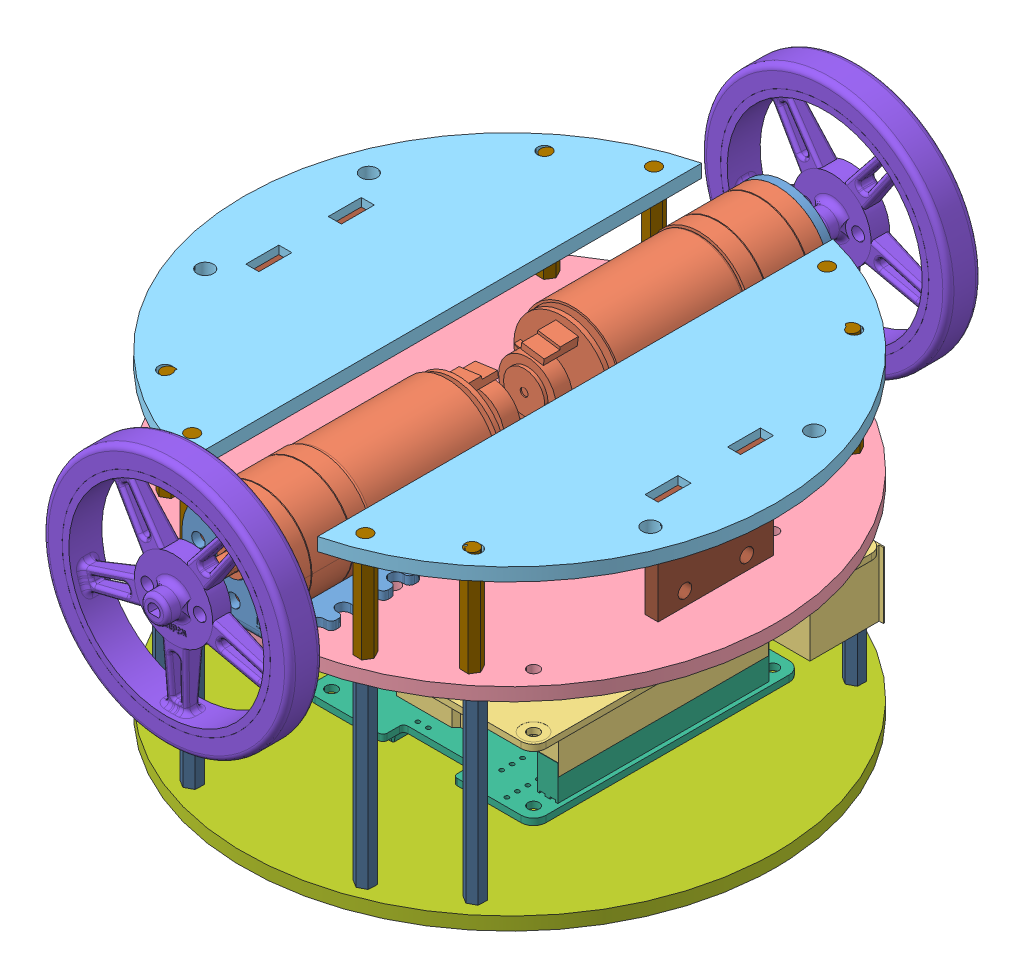
SolidWorks assembly Fleet v1.0, configuration Default. Lengths in mm.
Overall size (129 95.35 170.77).
30 component instances, 11 part files, 66 mates.
Components (placement in the parent):
- pololu-25d-mm-metal-gearmotor-bracket-1: pololu-25d-mm-metal-gearmotor-bracket [Default] at (11.9651 32.2947 52.3664) size (25 27 52)
- 25d-metal-gearmotor-20.4-encoder.step-1: 25d-metal-gearmotor-20.4-encoder.step [Default] at (41.8401 33.2947 46.4914) x (-1 0 0) z (0 0 1) size (25 32.85 74)
- 25d-metal-gearmotor-20.4-encoder.step-2: 25d-metal-gearmotor-20.4-encoder.step [Default] at (-19.9099 33.2947 -46.7586) x (1 0 0) z (0 0 -1) size (25 32.85 74)
- pololu-25d-mm-metal-gearmotor-bracket-2: pololu-25d-mm-metal-gearmotor-bracket [Default] at (9.9651 32.2947 -52.6336) x (-1 0 0) z (0 0 -1) size (25 27 52)
- Rpi3Bplus-1: Rpi3Bplus [Default] at (3.2536 5.5943 42.3664) x (0 0 -1) z (-1 0 0) size (87.03 17.52 58.47)
- Main Plate 1-1: Main Plate 1 [Default] at (25.4205 18.7947 0.2329) x (1 0 0) z (0 -1 0) size (129 129 3.17)
- SubPlate 1-1: SubPlate 1 [Default] at (26.8901 43.9697 0.2329) x (1 0 0) z (0 -1 0) size (48.58 125.01 3.17)
- SubPlate 1-2: SubPlate 1 [Default] at (-4.9599 43.9697 -0.5) x (-1 0 0) z (0 -1 0) size (48.58 125.01 3.17)
- dual-tb9051ftg-motor-driver-raspberry-pi.step-1: dual-tb9051ftg-motor-driver-raspberry-pi.step [Default] at (3.2536 -9.9043 42.3664) x (0 0 -1) z (0 -1 0) size (65 56 20.07)
- Top Plate-1: Top Plate [Default] at (25.9074 -29.3803 -5.7671) x (1 0 0) z (0 -1 0) size (129 129 3.17)
- pololu-wheel-60x8mm-black-1: pololu-wheel-60x8mm-black [Default] at (11.4421 32.7947 79.6164) x (0 0 -1) z (-1 0 0) size (11 60 60)
- pololu-wheel-60x8mm-black-2: pololu-wheel-60x8mm-black [Default] at (11.3417 32.7947 -80.154) x (0 0 -1) z (-1 0 0) size (11 60 60)
- 22mm Standoff-1: 22mm Standoff [Default] at (31.9651 18.7947 55.8664) size (4.39 28.35 3.87)
- 22mm Standoff-2: 22mm Standoff [Default] at (-25.8852 18.7947 -46.1336) size (4.39 28.35 3.87)
- 22mm Standoff-3: 22mm Standoff [Default] at (-10.0349 18.7947 -56.1336) size (4.39 28.35 3.87)
- 22mm Standoff-4: 22mm Standoff [Default] at (47.8154 18.7947 -46.1336) size (4.39 28.35 3.87)
- 22mm Standoff-5: 22mm Standoff [Default] at (47.8154 18.7947 45.8664) size (4.39 28.35 3.87)
- 22mm Standoff-6: 22mm Standoff [Default] at (31.9651 18.7947 -56.1336) size (4.39 28.35 3.87)
- 22mm Standoff-7: 22mm Standoff [Default] at (-10.0349 18.7947 55.8664) size (4.39 28.35 3.87)
- 22mm Standoff-8: 22mm Standoff [Default] at (-25.8852 40.7947 45.8664) x (0.837169 0 0.546944) z (0.546944 0 -0.837169) size (4.39 28.35 3.87)
- 45mm Standoff-1: 45mm Standoff [Default] at (-10.0349 15.6197 55.8664) x (-0.837169 0 -0.546944) z (-0.546944 0 0.837169) size (4.39 48.18 3.83)
- 45mm Standoff-2: 45mm Standoff [Default] at (31.9651 15.6197 55.8664) x (0.837169 0 0.546944) z (0.546944 0 -0.837169) size (4.39 48.18 3.83)
- 45mm Standoff-3: 45mm Standoff [Default] at (-10.0349 15.6197 -56.1336) x (-0.837169 0 -0.546944) z (-0.546944 0 0.837169) size (4.39 48.18 3.83)
- 45mm Standoff-4: 45mm Standoff [Default] at (-26.6691 15.6197 -46.1336) x (-0.837169 0 -0.546944) z (-0.546944 0 0.837169) size (4.39 48.18 3.83)
- 45mm Standoff-6: 45mm Standoff [Default] at (48.5993 15.6197 -46.1336) x (-0.837169 0 -0.546944) z (-0.546944 0 0.837169) size (4.39 48.18 3.83)
- 45mm Standoff-7: 45mm Standoff [Default] at (31.9651 15.6197 -56.1336) x (-0.837169 0 -0.546944) z (-0.546944 0 0.837169) size (4.39 48.18 3.83)
- 45mm Standoff-8: 45mm Standoff [Default] at (48.5993 15.6197 45.8664) x (-0.837169 0 -0.546944) z (-0.546944 0 0.837169) size (4.39 48.18 3.83)
- 45mm Standoff-9: 45mm Standoff [Default] at (-26.6691 15.6197 45.8664) x (0.837169 0 0.546944) z (0.546944 0 -0.837169) size (4.39 48.18 3.83)
- Time of Flight Holder-1: Time of Flight Holder [Default] at (-35.8599 28.7947 -0.1336) x (0 0 -1) z (-1 0 0) size (28 26.35 3.17)
- Time of Flight Holder-2: Time of Flight Holder [Default] at (60.9651 28.7947 -0.1336) x (0 0 -1) z (-1 0 0) size (28 26.35 3.17)
Mates (geometry in assembly coordinates):
- Concentric1: concentric: circle of pololu-25d-mm-metal-gearmotor-bracket-1; circle of 25d-metal-gearmotor-20.4-encoder.step-1
- Concentric2: concentric: circle of pololu-25d-mm-metal-gearmotor-bracket-1; circle of 25d-metal-gearmotor-20.4-encoder.step-1
- Coincident1: coincident: plane of pololu-25d-mm-metal-gearmotor-bracket-1 through (23.4651 20.7947 64.8664) normal (0 0 -1); plane of 25d-metal-gearmotor-20.4-encoder.step-1 through (10.9651 33.2947 64.8664) normal (0 0 1)
- Concentric3: concentric: circle of 25d-metal-gearmotor-20.4-encoder.step-2; circle of pololu-25d-mm-metal-gearmotor-bracket-2
- Concentric4: concentric: circle of 25d-metal-gearmotor-20.4-encoder.step-2; circle of pololu-25d-mm-metal-gearmotor-bracket-2
- Coincident2: coincident: plane of 25d-metal-gearmotor-20.4-encoder.step-2 through (10.9651 33.2947 -65.1336) normal (0 0 -1); plane of pololu-25d-mm-metal-gearmotor-bracket-2 through (-1.5349 20.7947 -65.1336) normal (0 0 1)
- Coincident3: coincident: plane of pololu-25d-mm-metal-gearmotor-bracket-1 through (23.4651 18.7947 64.8664) normal (0 -1 0); plane of pololu-25d-mm-metal-gearmotor-bracket-2 through (-1.5349 18.7947 -65.1336) normal (0 -1 0)
- Coincident5: coincident: plane of pololu-25d-mm-metal-gearmotor-bracket-1 through (-1.5349 21.4297 64.2314) normal (-1 0 0); plane of pololu-25d-mm-metal-gearmotor-bracket-2 through (-1.5349 21.4297 -67.1336) normal (-1 0 0)
- Distance6: distance = 10 mm: plane of Rpi3Bplus-1 through (6.2536 5.6197 -39.6336) normal (0 1 0); plane of Main Plate 1-1 through (10.9651 15.6197 -0.1336) normal (0 -1 0)
- Concentric13: concentric: circle of Main Plate 1-1; circle of SubPlate 1-1
- Concentric14: concentric: circle of Main Plate 1-1; circle of SubPlate 1-1
- Distance7: distance = 22 mm: plane of SubPlate 1-1 through (10.9651 40.7947 -0.1336) normal (0 -1 0); plane of Main Plate 1-1 through (10.9651 18.7947 -0.1336) normal (0 1 0)
- Concentric15: concentric: circle of Main Plate 1-1; circle of SubPlate 1-2
- Concentric16: concentric: circle of Main Plate 1-1; circle of SubPlate 1-2
- Distance8: distance = 22 mm: plane of SubPlate 1-2 through (10.9651 40.7947 -0.1336) normal (0 -1 0); plane of Main Plate 1-1 through (10.9651 18.7947 -0.1336) normal (0 1 0)
- Distance9: distance = 14 mm: plane of Rpi3Bplus-1 through (56.2536 4.0957 39.3664) normal (0 -1 0); plane of dual-tb9051ftg-motor-driver-raspberry-pi.step-1 through (6.2536 -9.9043 39.3664) normal (0 1 0)
- Coincident28: coincident: plane of Rpi3Bplus-1 through (59.2536 4.1211 39.3664) normal (1 0 0); plane of dual-tb9051ftg-motor-driver-raspberry-pi.step-1 through (59.2536 -11.4791 39.3664) normal (1 0 0)
- Coincident29: coincident: plane of Rpi3Bplus-1 through (6.2536 4.1211 42.3664) normal (0 0 1); plane of dual-tb9051ftg-motor-driver-raspberry-pi.step-1 through (40.7536 -11.4791 42.3664) normal (0 0 1)
- Concentric17: concentric: circle of Main Plate 1-1; circle of Top Plate-1
- Concentric18: concentric: cylinder of Main Plate 1-1 through (31.9651 15.6197 55.8664) axis (0 1 0) radius 1.65; circle of Top Plate-1
- Distance10: distance = 45 mm: plane of Top Plate-1 through (10.9651 -29.3803 -0.1336) normal (0 1 0); plane of Main Plate 1-1 through (10.9651 15.6197 -0.1336) normal (0 -1 0)
- Coincident34: coincident: plane of 25d-metal-gearmotor-20.4-encoder.step-1 through (10.9651 31.7947 69.3664) normal (0 -1 0); plane of pololu-wheel-60x8mm-black-1 through (12.5601 31.7947 75.6164) normal (0 1 0)
- Parallel8: parallel: cylinder of 25d-metal-gearmotor-20.4-encoder.step-1 through (10.9651 33.2947 64.8664) axis (0 0 1) radius 2; cylinder of pololu-wheel-60x8mm-black-1 through (11.4421 32.7947 75.6164) axis (0 0 1) radius 1.5
- Coincident38: coincident: plane of 25d-metal-gearmotor-20.4-encoder.step-2 through (10.9651 31.7947 -69.6336) normal (0 -1 0); plane of pololu-wheel-60x8mm-black-2 through (12.4598 31.7947 -84.154) normal (0 1 0)
- Parallel9: parallel: cylinder of 25d-metal-gearmotor-20.4-encoder.step-2 through (10.9651 33.2947 -65.1336) axis (0 0 -1) radius 2; cylinder of pololu-wheel-60x8mm-black-2 through (11.3417 32.7947 -84.154) axis (0 0 1) radius 1.5
- Concentric27: concentric: cylinder of Main Plate 1-1 through (31.9651 15.6197 55.8664) axis (0 1 0) radius 1.65; cylinder of 22mm Standoff-1 through (31.9651 15.6197 55.8664) axis (0 1 0) radius 1.65
- Concentric28: concentric: circle of SubPlate 1-1; cylinder of 22mm Standoff-1 through (31.9651 43.9697 55.8664) axis (0 -1 0) radius 1.65
- Coincident40: coincident: plane of SubPlate 1-1 through (10.9651 40.7947 -0.1336) normal (0 -1 0); plane of 22mm Standoff-1 through (31.9651 40.7947 55.8664) normal (0 1 0)
- Concentric29: concentric: cylinder of Main Plate 1-1 through (47.8154 15.6197 45.8664) axis (0 1 0) radius 1.65; cylinder of 22mm Standoff-5 through (47.8154 15.6197 45.8664) axis (0 1 0) radius 1.65
- Coincident41: coincident: plane of Main Plate 1-1 through (10.9651 18.7947 -0.1336) normal (0 1 0); plane of 22mm Standoff-5 through (47.8154 18.7947 45.8664) normal (0 -1 0)
- Concentric30: concentric: cylinder of Main Plate 1-1 through (47.8154 15.6197 -46.1336) axis (0 1 0) radius 1.65; cylinder of 22mm Standoff-4 through (47.8154 15.6197 -46.1336) axis (0 1 0) radius 1.65
- Coincident42: coincident: plane of Main Plate 1-1 through (10.9651 18.7947 -0.1336) normal (0 1 0); plane of 22mm Standoff-4 through (47.8154 18.7947 -46.1336) normal (0 -1 0)
- Concentric31: concentric: cylinder of Main Plate 1-1 through (31.9651 15.6197 -56.1336) axis (0 1 0) radius 1.65; cylinder of 22mm Standoff-6 through (31.9651 15.6197 -56.1336) axis (0 1 0) radius 1.65
- Coincident43: coincident: plane of Main Plate 1-1 through (10.9651 18.7947 -0.1336) normal (0 1 0); plane of 22mm Standoff-6 through (31.9651 18.7947 -56.1336) normal (0 -1 0)
- Concentric32: concentric: cylinder of Main Plate 1-1 through (-10.0349 15.6197 -56.1336) axis (0 1 0) radius 1.65; cylinder of 22mm Standoff-3 through (-10.0349 15.6197 -56.1336) axis (0 1 0) radius 1.65
- Coincident44: coincident: plane of Main Plate 1-1 through (10.9651 18.7947 -0.1336) normal (0 1 0); plane of 22mm Standoff-3 through (-10.0349 18.7947 -56.1336) normal (0 -1 0)
- Concentric33: concentric: cylinder of Main Plate 1-1 through (-25.8852 15.6197 -46.1336) axis (0 1 0) radius 1.65; cylinder of 22mm Standoff-2 through (-25.8852 15.6197 -46.1336) axis (0 1 0) radius 1.65
- Coincident45: coincident: plane of Main Plate 1-1 through (10.9651 18.7947 -0.1336) normal (0 1 0); plane of 22mm Standoff-2 through (-25.8852 18.7947 -46.1336) normal (0 -1 0)
- Concentric34: concentric: cylinder of Main Plate 1-1 through (-25.8852 15.6197 45.8664) axis (0 1 0) radius 1.65; cylinder of 22mm Standoff-8 through (-25.8852 43.9697 45.8664) axis (0 -1 0) radius 1.65
- Coincident46: coincident: plane of Main Plate 1-1 through (10.9651 18.7947 -0.1336) normal (0 1 0); plane of 22mm Standoff-8 through (-25.8852 18.7947 45.8664) normal (0 -1 0)
- Concentric35: concentric: cylinder of Main Plate 1-1 through (-10.0349 15.6197 55.8664) axis (0 1 0) radius 1.65; cylinder of 22mm Standoff-7 through (-10.0349 15.6197 55.8664) axis (0 1 0) radius 1.65
- Coincident47: coincident: plane of Main Plate 1-1 through (10.9651 18.7947 -0.1336) normal (0 1 0); plane of 22mm Standoff-7 through (-10.0349 18.7947 55.8664) normal (0 -1 0)
- Concentric36: concentric: cylinder of Top Plate-1 through (-26.6691 -32.5553 45.8664) axis (0 1 0) radius 1.65; cylinder of 45mm Standoff-9 through (-26.6691 -32.5553 45.8664) axis (0 1 0) radius 1.65
- Coincident48: coincident: plane of Main Plate 1-1 through (10.9651 15.6197 -0.1336) normal (0 -1 0); plane of 45mm Standoff-9 through (-26.6691 15.6197 45.8664) normal (0 1 0)
- Coincident49: coincident: plane of Main Plate 1-1 through (10.9651 15.6197 -0.1336) normal (0 -1 0); plane of 45mm Standoff-1 through (-10.0349 15.6197 55.8664) normal (0 1 0)
- Concentric37: concentric: cylinder of Top Plate-1 through (-10.0349 -32.5553 55.8664) axis (0 1 0) radius 1.65; cylinder of 45mm Standoff-1 through (-10.0349 -32.5553 55.8664) axis (0 1 0) radius 1.65
- Coincident50: coincident: plane of Main Plate 1-1 through (10.9651 15.6197 -0.1336) normal (0 -1 0); plane of 45mm Standoff-2 through (31.9651 15.6197 55.8664) normal (0 1 0)
- Concentric38: concentric: cylinder of Top Plate-1 through (31.9651 -32.5553 55.8664) axis (0 1 0) radius 1.65; cylinder of 45mm Standoff-2 through (31.9651 -32.5553 55.8664) axis (0 1 0) radius 1.65
- Coincident51: coincident: plane of Main Plate 1-1 through (10.9651 15.6197 -0.1336) normal (0 -1 0); plane of 45mm Standoff-8 through (48.5993 15.6197 45.8664) normal (0 1 0)
- Concentric39: concentric: cylinder of Top Plate-1 through (48.5993 -32.5553 45.8664) axis (0 1 0) radius 1.65; cylinder of 45mm Standoff-8 through (48.5993 -32.5553 45.8664) axis (0 1 0) radius 1.65
- Coincident52: coincident: plane of Main Plate 1-1 through (10.9651 15.6197 -0.1336) normal (0 -1 0); plane of 45mm Standoff-6 through (48.5993 15.6197 -46.1336) normal (0 1 0)
- Concentric40: concentric: cylinder of Top Plate-1 through (48.5993 -32.5553 -46.1336) axis (0 1 0) radius 1.65; cylinder of 45mm Standoff-6 through (48.5993 -32.5553 -46.1336) axis (0 1 0) radius 1.65
- Coincident53: coincident: plane of Main Plate 1-1 through (10.9651 15.6197 -0.1336) normal (0 -1 0); plane of 45mm Standoff-7 through (31.9651 15.6197 -56.1336) normal (0 1 0)
- Concentric41: concentric: cylinder of Top Plate-1 through (31.9651 -32.5553 -56.1336) axis (0 1 0) radius 1.65; cylinder of 45mm Standoff-7 through (31.9651 -32.5553 -56.1336) axis (0 1 0) radius 1.65
- Coincident54: coincident: plane of Main Plate 1-1 through (10.9651 15.6197 -0.1336) normal (0 -1 0); plane of 45mm Standoff-3 through (-10.0349 15.6197 -56.1336) normal (0 1 0)
- Concentric42: concentric: cylinder of Top Plate-1 through (-10.0349 -32.5553 -56.1336) axis (0 1 0) radius 1.65; cylinder of 45mm Standoff-3 through (-10.0349 -32.5553 -56.1336) axis (0 1 0) radius 1.65
- Coincident55: coincident: plane of Main Plate 1-1 through (10.9651 15.6197 -0.1336) normal (0 -1 0); plane of 45mm Standoff-4 through (-26.6691 15.6197 -46.1336) normal (0 1 0)
- Concentric43: concentric: cylinder of Top Plate-1 through (-26.6691 -32.5553 -46.1336) axis (0 1 0) radius 1.65; cylinder of 45mm Standoff-4 through (-26.6691 -32.5553 -46.1336) axis (0 1 0) radius 1.65
- Concentric44: concentric: cylinder of Rpi3Bplus-1 through (55.7536 4.1211 38.8664) axis (0 1 0) radius 1.375; cylinder of Main Plate 1-1 through (55.7536 15.6197 38.8664) axis (0 1 0) radius 1.4
- Concentric45: concentric: cylinder of Rpi3Bplus-1 through (6.7536 4.1211 -19.1336) axis (0 1 0) radius 1.375; cylinder of Main Plate 1-1 through (6.7536 15.6197 -19.1336) axis (0 1 0) radius 1.4
- Coincident56: coincident: plane of Main Plate 1-1 through (10.9651 18.7947 -0.1336) normal (0 1 0); plane of Time of Flight Holder-1 through (-39.0349 18.7947 -0.1336) normal (0 -1 0)
- Coincident58: coincident: line of Main Plate 1-1 through (-39.0349 15.6197 -6.1336) axis (0 0 -1); line of Time of Flight Holder-1 through (-39.0349 15.6197 -6.1336) axis (0 0 -1)
- Coincident59: coincident: line of Main Plate 1-1 through (-39.0349 15.6197 -14.1336) axis (1 0 0); line of Time of Flight Holder-1 through (-39.0349 15.6197 -14.1336) axis (1 0 0)
- Coincident60: coincident: plane of Main Plate 1-1 through (10.9651 18.7947 -0.1336) normal (0 1 0); plane of Time of Flight Holder-2 through (57.7901 18.7947 -0.1336) normal (0 -1 0)
- Coincident61: coincident: line of Main Plate 1-1 through (57.7901 15.6197 -14.1336) axis (1 0 0); line of Time of Flight Holder-2 through (57.7901 15.6197 -14.1336) axis (1 0 0)
- Coincident62: coincident: line of Main Plate 1-1 through (60.9651 15.6197 -14.1336) axis (0 0 1); line of Time of Flight Holder-2 through (60.9651 15.6197 -6.1336) axis (0 0 -1)
